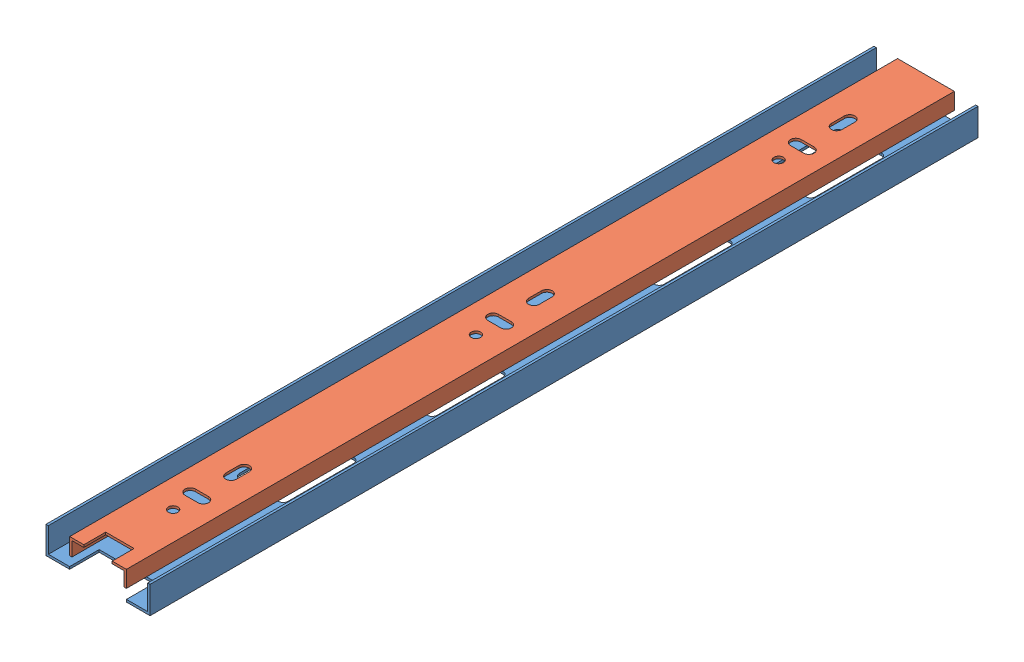
SolidWorks assembly 滑轨装配体, configuration 默认. Lengths in mm.
Overall size (44 12 350).
2 component instances, 2 part files, 3 mates.
Components (placement in the parent):
- 滑轨1-1: 滑轨1 [默认] at (6.4098 2.026 175) size (44 11.5 350)
- 滑轨2-1: 滑轨2 [默认] at (-5.7763 4.4377 525) x (1 0 0) z (0 0 -1) size (24 7 350)
Mates (geometry in assembly coordinates):
- 距离1: distance = 11 mm: plane of 滑轨2-1 through (-17.7763 7.9377 175) normal (0 1 0); plane of 滑轨1-1 through (-26.7763 -3.0623 525) normal (0 1 0)
- 对称2: symmetric: plane of 滑轨2-1 through (-17.7763 0.9377 175) normal (-1 0 0); plane of 滑轨2-1 through (6.2237 0.9377 175) normal (1 0 0); plane of assembly
- LimitDistance1: limit distance = 0 mm: plane of 滑轨2-1 through (-5.7763 4.4377 175) normal (0 0 -1); plane of 滑轨1-1 through (6.4098 2.026 175) normal (0 0 -1)
